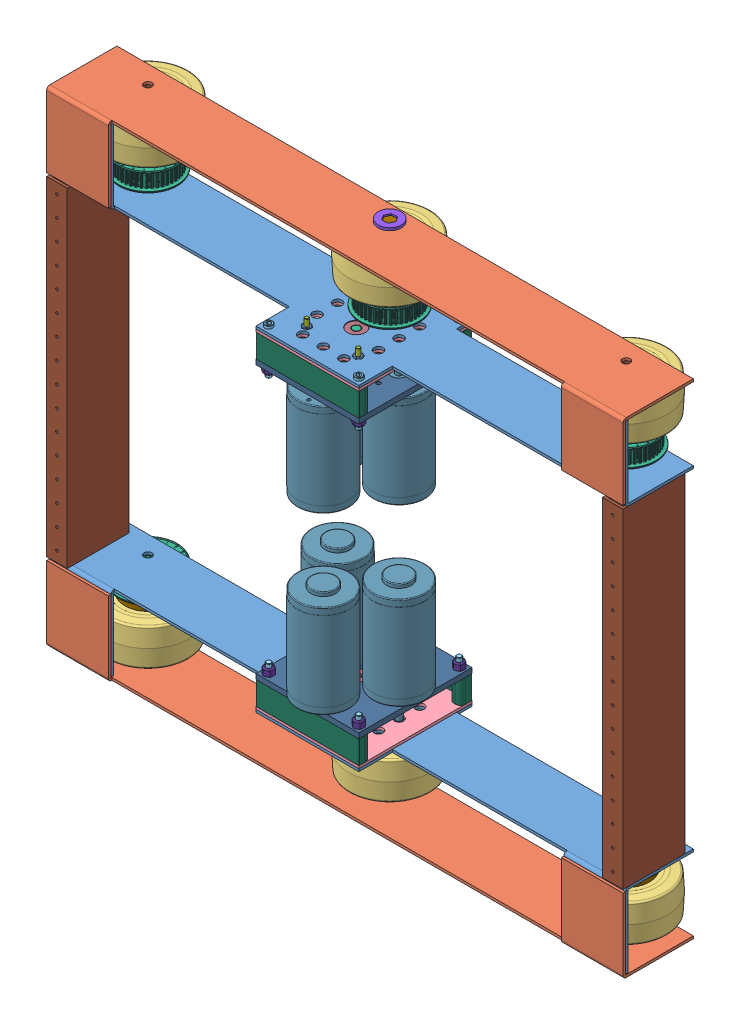
SolidWorks assembly DRIVE TRAIN, configuration Default. Lengths in mm.
Overall size (733.26 604.72 237.72).
116 component instances, 29 part files, 8 mates.
Components (placement in the parent):
- wheel well assembly-1: wheel well assembly [Default] at (270.1383 302.7916 604.4293) size (722.23 256.81 237.72)
  - interior wheel well-1: interior wheel well [Default] at (64.0134 461.709 590.6846) size (711.2 92.08 139.7)
  - exterior wheel well-1: exterior wheel well [Default] at (562.6642 549.3506 593.8596) x (-1 0 0) z (0 0 1) size (711.2 92.07 86.72)
  - wheel live axis-1: wheel live axis [Default] at (260.8798 526.3795 516.7847) x (0 -1 0) z (0.083749 0 0.996487) size (93.59 101.6 101.6)
    - colson wheel-1: colson wheel [Default] at (7.8533 43.785 105.4789) size (47.77 101.6 101.6)
    - hub live axis-1: hub live axis [Default] at (-17.6186 43.785 105.4789) x (0 -0.5 -0.866025) z (1 0 0) size (34.92 34.92 48.22)
    - versahub .5 in hex-2: versahub .5 in hex [Default] at (44.4376 43.785 105.4789) x (-1 0 0) z (0 0 -1) size (12.7 55.88 55.88)
    - pulley-1: pulley [Default] at (42.8501 43.785 105.4789) x (0 0.128986 0.991646) z (-1 0 0) size (73 73 23.01)
    - versahub 1.125 in bearing pilot-1: versahub 1.125 in bearing pilot [Default] at (38.0876 43.785 105.4789) x (0 -0.011158 0.999938) z (0 0.999938 0.011158) size (55.88 12.7 55.88)
    - hex bearing for live axis-1: hex bearing for live axis [Default] at (-30.3186 43.785 105.4789) x (0 -0.5 0.866025) z (0 0.866025 0.5) size (31.12 7.94 31.12)
  - wheel dead axis-1: wheel dead axis [Default] at (704.3486 556.3797 624.3714) x (0 -1 0) z (-0.767501 0 -0.641048) size (87.16 101.6 101.6)
    - colson wheel-1: colson wheel [Default] at (34.5983 59.2472 75.5116) size (47.77 101.6 101.6)
    - hub dead axis-1: hub dead axis [Default] at (61.6576 59.2472 75.5116) x (0 0.55376 0.832676) z (-1 0 0) size (57.15 57.15 47.62)
    - bearing-1: bearing [Default] at (57.6889 59.2472 75.5116) size (7.14 22.23 22.23)
    - bearing-2: bearing [Default] at (17.2074 59.2472 75.5116) size (7.14 22.23 22.23)
    - versahub 1.125 in bearing pilot-1: versahub 1.125 in bearing pilot [Default] at (68.0076 59.2472 75.5116) x (0 1 0) z (0 0 1) size (55.88 12.7 55.88)
    - pulley-1: pulley [Default] at (90.5951 59.2472 75.5116) x (0 0 -1) z (1 0 0) size (73 73 23.01)
    - spacer for dead axis-2: spacer for dead axis [Default] at (6.0316 59.2472 75.5116) x (0 0.370269 -0.928924) z (1 0 0) size (30.04 30.04 11.18)
  - wheel dead axis-2: wheel dead axis [Default] at (-40.9827 556.3797 545.9255) x (0 -1 0) z (0 0 1) size (87.16 101.6 101.6)
    - colson wheel-1: colson wheel [Default] at (34.5983 59.2472 75.5116) size (47.77 101.6 101.6)
    - hub dead axis-1: hub dead axis [Default] at (61.6576 59.2472 75.5116) x (0 0.55376 0.832676) z (-1 0 0) size (57.15 57.15 47.62)
    - bearing-1: bearing [Default] at (57.6889 59.2472 75.5116) size (7.14 22.23 22.23)
    - bearing-2: bearing [Default] at (17.2074 59.2472 75.5116) size (7.14 22.23 22.23)
    - versahub 1.125 in bearing pilot-1: versahub 1.125 in bearing pilot [Default] at (68.0076 59.2472 75.5116) x (0 1 0) z (0 0 1) size (55.88 12.7 55.88)
    - pulley-1: pulley [Default] at (90.5951 59.2472 75.5116) x (0 0 -1) z (1 0 0) size (73 73 23.01)
    - spacer for dead axis-2: spacer for dead axis [Default] at (6.0316 59.2472 75.5116) x (0 0.370269 -0.928924) z (1 0 0) size (30.04 30.04 11.18)
  - 3CIM Gearbox with plate - AM14U-1: 3CIM Gearbox with plate - AM14U [Default] at (236.214 396.9903 599.8023) x (0.425715 0 -0.904857) z (0 -1 0) size (180.67 174.39 255.11)
    - 500 E-klip-1: 500 E-klip [Default] at (16.1298 77.6456 -43.9601) x (-0.987566 -0.157207 0) z (0 0 1) size (19.07 20.96 1.27)
    - FR6ZZ Bearing-1: FR6ZZ Bearing [Default] at (-13.0875 102.2889 -55.8473) x (0.991783 0.127931 0) z (0 0 -1) size (24.69 24.69 7.16)
    - CIM Motor SW-1: CIM Motor SW [Default] at (-100.8929 87.6226 -3.2185) x (0 1 0) z (0 0 -1) size (64.01 64.01 154.94)
    - ex-2508 Spacer-1: ex-2508 Spacer [Default] at (-92.2921 67.2369 -57.3713) x (0.425715 0.904857 0) z (0 0 1) size (127 14.35 28.75)
    - CIM Motor SW-2: CIM Motor SW [Default] at (-101.4872 6.1263 -3.2185) x (-0.762709 0.646742 0) z (0 0 -1) size (64.01 64.01 154.94)
    - Toughbox 14T Small Cluster-1: Toughbox 14T Small Cluster [Default] at (-21.1033 95.1629 -40.7851) x (-0.837052 0.547123 0) z (0 0 -1) size (20.03 20.32 15.25)
    - 14-20 Nylock Nut_97135A210-1: 14-20 Nylock Nut_97135A210 [Default] at (19.7748 14.5119 -22.2685) x (1 0 0) z (0 -1 0) size (11.11 8.13 12.83)
    - Toughbox 50T Large Cluster-1: Toughbox 50T Large Cluster [Default] at (-21.1033 95.1629 -40.7851) x (-0.055297 -0.99847 0) z (0 0 1) size (65.97 66.04 10.34)
    - 10-32 Nylock Jam Nut_90633A411-1: 10-32 Nylock Jam Nut_90633A411 [Default] at (-34.2188 136.4219 -60.5463) x (0.976554 -0.215274 0) z (0.215274 0.976554 0) size (9.53 4.55 11)
    - 14-20 Nylock Nut_97135A210-2: 14-20 Nylock Nut_97135A210 [Default] at (67.0932 115.0872 -22.2685) x (1 0 0) z (0 -1 0) size (11.11 8.13 12.83)
    - 14-20 Nylock Nut_97135A210-3: 14-20 Nylock Nut_97135A210 [Default] at (-92.2921 67.2369 -22.2685) x (1 0 0) z (0 -1 0) size (11.11 8.13 12.83)
    - ex-2508 Spacer-2: ex-2508 Spacer [Default] at (67.0932 115.0872 -57.3713) x (-0.425715 -0.904857 0) z (0 0 1) size (127 14.35 28.75)
    - Toughbox 50T Output-1: Toughbox 50T Output [Default] at (16.1298 77.6456 -45.1793) x (1 0 0) z (0 0 -1) size (65.97 66.04 10.62)
    - FR6ZZ Bearing-2: FR6ZZ Bearing [Default] at (-30.482 100.3659 -30.1425) x (-0.995778 -0.091798 0) z (0 0 1) size (24.69 24.69 7.16)
    - FR8ZZ Hex Bearing-1: FR8ZZ Hex Bearing [Default] at (16.1298 77.6456 -63.2666) size (31.12 31.12 7.93)
    - FR6ZZ Bearing-3: FR6ZZ Bearing [Default] at (7.2113 83.6032 -29.1773) x (-0.999955 -0.009486 0) z (0 0 1) size (24.69 24.69 7.16)
    - 3CIM TB Special Shaft Plate-1: 3CIM TB Special Shaft Plate [Default] at (16.1298 77.6456 -57.3713) x (0.425715 0.904857 0) z (0 0 1) size (127 139.7 3.17)
    - 10-32 Nylock Jam Nut_90633A411-2: 10-32 Nylock Jam Nut_90633A411 [Default] at (-61.2517 78.9634 -60.5463) x (0.733502 -0.679687 0) z (0.679687 0.733502 0) size (9.53 4.55 11)
    - SHCS 14-20 x 2-1: SHCS 14-20 x 2 [Default] at (-44.9737 167.8122 -67.0995) x (0.867127 -0.498087 0) z (0.498087 0.867127 0) size (9.53 57.35 9.53)
    - CIM Motor SW-3: CIM Motor SW [Default] at (-138.5887 47.3684 -3.2185) x (0.249226 0.968445 0) z (0 0 -1) size (64.01 64.01 154.94)
    - SHCS 14-20 x 2-2: SHCS 14-20 x 2 [Default] at (67.0932 115.0872 -67.0995) x (1 0 0) z (0 1 0) size (9.53 57.35 9.53)
    - TB Hex Shaft-1: TB Hex Shaft [Default] at (-63.6271 92.3312 -31.1331) x (-0.892349 -0.451347 0) z (-0.451347 0.892349 0) size (11 38.23 9.52)
    - 10-32x0625_shcs_HX-SHCS 0.19-32x1.375x1-C-1: 10-32x0625_shcs_HX-SHCS 0.19-32x1.375x1-C [Default] at (-34.2188 136.4219 -52.5453) x (0 0 -1) z (0.658531 0.752554 0) size (20.7 7.94 7.94)
    - Toughbox d29a-1: Toughbox d29a [Default] at (16.1298 77.6456 -22.2685) x (-0.904857 0.425715 0) z (0.425715 0.904857 0) size (19.05 6.1 50.8)
    - SHCS 14-20 x 2-3: SHCS 14-20 x 2 [Default] at (19.7748 14.5119 -67.0995) x (1 0 0) z (0 1 0) size (9.53 57.35 9.53)
    - 14-20 Nylock Nut_97135A210-4: 14-20 Nylock Nut_97135A210 [Default] at (-44.9737 167.8122 -22.2685) x (1 0 0) z (0 -1 0) size (11.11 8.13 12.83)
    - TB Output Shaft Hex L-Base 2-1: TB Output Shaft Hex L-Base 2 [Default] at (20.8476 119.155 -54.5773) x (0.5 0.866025 0) z (-0.866025 0.5 0) size (14.66 148.64 12.7)
    - 3CIM TB Special Motor Plate-1: 3CIM TB Special Motor Plate [Default] at (16.1298 77.6456 -57.1935) x (0.425715 0.904857 0) z (0 0 1) size (127 139.7 6.35)
    - 10-32x0625_shcs_HX-SHCS 0.19-32x1.375x1-C-2: 10-32x0625_shcs_HX-SHCS 0.19-32x1.375x1-C [Default] at (-61.2517 78.9634 -52.5453) x (0 0 -1) z (1 0 0) size (20.7 7.94 7.94)
    - SHCS 14-20 x 2-4: SHCS 14-20 x 2 [Default] at (-92.2921 67.2369 -67.0995) x (1 0 0) z (0 1 0) size (9.53 57.35 9.53)
- wheel well assembly-2: wheel well assembly [Default] at (896.816 811.4646 604.4293) x (-1 0 0) z (0 0 1) size (722.23 256.81 237.72)
  - interior wheel well-1: interior wheel well [Default] at (64.0134 461.709 590.6846) size (711.2 92.08 139.7)
  - exterior wheel well-1: exterior wheel well [Default] at (562.6642 549.3506 593.8596) x (-1 0 0) z (0 0 1) size (711.2 92.07 86.72)
  - wheel live axis-1: wheel live axis [Default] at (260.8798 526.3795 516.7847) x (0 -1 0) z (0.083749 0 0.996487) size (93.59 101.6 101.6)
    - colson wheel-1: colson wheel [Default] at (7.8533 43.785 105.4789) size (47.77 101.6 101.6)
    - hub live axis-1: hub live axis [Default] at (-17.6186 43.785 105.4789) x (0 -0.5 -0.866025) z (1 0 0) size (34.92 34.92 48.22)
    - versahub .5 in hex-2: versahub .5 in hex [Default] at (44.4376 43.785 105.4789) x (-1 0 0) z (0 0 -1) size (12.7 55.88 55.88)
    - pulley-1: pulley [Default] at (42.8501 43.785 105.4789) x (0 0.128986 0.991646) z (-1 0 0) size (73 73 23.01)
    - versahub 1.125 in bearing pilot-1: versahub 1.125 in bearing pilot [Default] at (38.0876 43.785 105.4789) x (0 -0.011158 0.999938) z (0 0.999938 0.011158) size (55.88 12.7 55.88)
    - hex bearing for live axis-1: hex bearing for live axis [Default] at (-30.3186 43.785 105.4789) x (0 -0.5 0.866025) z (0 0.866025 0.5) size (31.12 7.94 31.12)
  - wheel dead axis-1: wheel dead axis [Default] at (704.3486 556.3797 624.3714) x (0 -1 0) z (-0.767501 0 -0.641048) size (87.16 101.6 101.6)
    - colson wheel-1: colson wheel [Default] at (34.5983 59.2472 75.5116) size (47.77 101.6 101.6)
    - hub dead axis-1: hub dead axis [Default] at (61.6576 59.2472 75.5116) x (0 0.55376 0.832676) z (-1 0 0) size (57.15 57.15 47.62)
    - bearing-1: bearing [Default] at (57.6889 59.2472 75.5116) size (7.14 22.23 22.23)
    - bearing-2: bearing [Default] at (17.2074 59.2472 75.5116) size (7.14 22.23 22.23)
    - versahub 1.125 in bearing pilot-1: versahub 1.125 in bearing pilot [Default] at (68.0076 59.2472 75.5116) x (0 1 0) z (0 0 1) size (55.88 12.7 55.88)
    - pulley-1: pulley [Default] at (90.5951 59.2472 75.5116) x (0 0 -1) z (1 0 0) size (73 73 23.01)
    - spacer for dead axis-2: spacer for dead axis [Default] at (6.0316 59.2472 75.5116) x (0 0.370269 -0.928924) z (1 0 0) size (30.04 30.04 11.18)
  - wheel dead axis-2: wheel dead axis [Default] at (-40.9827 556.3797 545.9255) x (0 -1 0) z (0 0 1) size (87.16 101.6 101.6)
    - colson wheel-1: colson wheel [Default] at (34.5983 59.2472 75.5116) size (47.77 101.6 101.6)
    - hub dead axis-1: hub dead axis [Default] at (61.6576 59.2472 75.5116) x (0 0.55376 0.832676) z (-1 0 0) size (57.15 57.15 47.62)
    - bearing-1: bearing [Default] at (57.6889 59.2472 75.5116) size (7.14 22.23 22.23)
    - bearing-2: bearing [Default] at (17.2074 59.2472 75.5116) size (7.14 22.23 22.23)
    - versahub 1.125 in bearing pilot-1: versahub 1.125 in bearing pilot [Default] at (68.0076 59.2472 75.5116) x (0 1 0) z (0 0 1) size (55.88 12.7 55.88)
    - pulley-1: pulley [Default] at (90.5951 59.2472 75.5116) x (0 0 -1) z (1 0 0) size (73 73 23.01)
    - spacer for dead axis-2: spacer for dead axis [Default] at (6.0316 59.2472 75.5116) x (0 0.370269 -0.928924) z (1 0 0) size (30.04 30.04 11.18)
  - 3CIM Gearbox with plate - AM14U-1: 3CIM Gearbox with plate - AM14U [Default] at (236.214 396.9903 599.8023) x (0.425715 0 -0.904857) z (0 -1 0) size (180.67 174.39 255.11)
    - 500 E-klip-1: 500 E-klip [Default] at (16.1298 77.6456 -43.9601) x (-0.987566 -0.157207 0) z (0 0 1) size (19.07 20.96 1.27)
    - FR6ZZ Bearing-1: FR6ZZ Bearing [Default] at (-13.0875 102.2889 -55.8473) x (0.991783 0.127931 0) z (0 0 -1) size (24.69 24.69 7.16)
    - CIM Motor SW-1: CIM Motor SW [Default] at (-100.8929 87.6226 -3.2185) x (0 1 0) z (0 0 -1) size (64.01 64.01 154.94)
    - ex-2508 Spacer-1: ex-2508 Spacer [Default] at (-92.2921 67.2369 -57.3713) x (0.425715 0.904857 0) z (0 0 1) size (127 14.35 28.75)
    - CIM Motor SW-2: CIM Motor SW [Default] at (-101.4872 6.1263 -3.2185) x (-0.762709 0.646742 0) z (0 0 -1) size (64.01 64.01 154.94)
    - Toughbox 14T Small Cluster-1: Toughbox 14T Small Cluster [Default] at (-21.1033 95.1629 -40.7851) x (-0.837052 0.547123 0) z (0 0 -1) size (20.03 20.32 15.25)
    - 14-20 Nylock Nut_97135A210-1: 14-20 Nylock Nut_97135A210 [Default] at (19.7748 14.5119 -22.2685) x (1 0 0) z (0 -1 0) size (11.11 8.13 12.83)
    - Toughbox 50T Large Cluster-1: Toughbox 50T Large Cluster [Default] at (-21.1033 95.1629 -40.7851) x (-0.055297 -0.99847 0) z (0 0 1) size (65.97 66.04 10.34)
    - 10-32 Nylock Jam Nut_90633A411-1: 10-32 Nylock Jam Nut_90633A411 [Default] at (-34.2188 136.4219 -60.5463) x (0.976554 -0.215274 0) z (0.215274 0.976554 0) size (9.53 4.55 11)
    - 14-20 Nylock Nut_97135A210-2: 14-20 Nylock Nut_97135A210 [Default] at (67.0932 115.0872 -22.2685) x (1 0 0) z (0 -1 0) size (11.11 8.13 12.83)
    - 14-20 Nylock Nut_97135A210-3: 14-20 Nylock Nut_97135A210 [Default] at (-92.2921 67.2369 -22.2685) x (1 0 0) z (0 -1 0) size (11.11 8.13 12.83)
    - ex-2508 Spacer-2: ex-2508 Spacer [Default] at (67.0932 115.0872 -57.3713) x (-0.425715 -0.904857 0) z (0 0 1) size (127 14.35 28.75)
    - Toughbox 50T Output-1: Toughbox 50T Output [Default] at (16.1298 77.6456 -45.1793) x (1 0 0) z (0 0 -1) size (65.97 66.04 10.62)
    - FR6ZZ Bearing-2: FR6ZZ Bearing [Default] at (-30.482 100.3659 -30.1425) x (-0.995778 -0.091798 0) z (0 0 1) size (24.69 24.69 7.16)
    - FR8ZZ Hex Bearing-1: FR8ZZ Hex Bearing [Default] at (16.1298 77.6456 -63.2666) size (31.12 31.12 7.93)
    - FR6ZZ Bearing-3: FR6ZZ Bearing [Default] at (7.2113 83.6032 -29.1773) x (-0.999955 -0.009486 0) z (0 0 1) size (24.69 24.69 7.16)
    - 3CIM TB Special Shaft Plate-1: 3CIM TB Special Shaft Plate [Default] at (16.1298 77.6456 -57.3713) x (0.425715 0.904857 0) z (0 0 1) size (127 139.7 3.17)
    - 10-32 Nylock Jam Nut_90633A411-2: 10-32 Nylock Jam Nut_90633A411 [Default] at (-61.2517 78.9634 -60.5463) x (0.733502 -0.679687 0) z (0.679687 0.733502 0) size (9.53 4.55 11)
    - SHCS 14-20 x 2-1: SHCS 14-20 x 2 [Default] at (-44.9737 167.8122 -67.0995) x (0.867127 -0.498087 0) z (0.498087 0.867127 0) size (9.53 57.35 9.53)
    - CIM Motor SW-3: CIM Motor SW [Default] at (-138.5887 47.3684 -3.2185) x (0.249226 0.968445 0) z (0 0 -1) size (64.01 64.01 154.94)
    - SHCS 14-20 x 2-2: SHCS 14-20 x 2 [Default] at (67.0932 115.0872 -67.0995) x (1 0 0) z (0 1 0) size (9.53 57.35 9.53)
    - TB Hex Shaft-1: TB Hex Shaft [Default] at (-63.6271 92.3312 -31.1331) x (-0.892349 -0.451347 0) z (-0.451347 0.892349 0) size (11 38.23 9.52)
    - 10-32x0625_shcs_HX-SHCS 0.19-32x1.375x1-C-1: 10-32x0625_shcs_HX-SHCS 0.19-32x1.375x1-C [Default] at (-34.2188 136.4219 -52.5453) x (0 0 -1) z (0.658531 0.752554 0) size (20.7 7.94 7.94)
    - Toughbox d29a-1: Toughbox d29a [Default] at (16.1298 77.6456 -22.2685) x (-0.904857 0.425715 0) z (0.425715 0.904857 0) size (19.05 6.1 50.8)
    - SHCS 14-20 x 2-3: SHCS 14-20 x 2 [Default] at (19.7748 14.5119 -67.0995) x (1 0 0) z (0 1 0) size (9.53 57.35 9.53)
    - 14-20 Nylock Nut_97135A210-4: 14-20 Nylock Nut_97135A210 [Default] at (-44.9737 167.8122 -22.2685) x (1 0 0) z (0 -1 0) size (11.11 8.13 12.83)
    - TB Output Shaft Hex L-Base 2-1: TB Output Shaft Hex L-Base 2 [Default] at (20.8476 119.155 -54.5773) x (0.5 0.866025 0) z (-0.866025 0.5 0) size (14.66 148.64 12.7)
    - 3CIM TB Special Motor Plate-1: 3CIM TB Special Motor Plate [Default] at (16.1298 77.6456 -57.1935) x (0.425715 0.904857 0) z (0 0 1) size (127 139.7 6.35)
    - 10-32x0625_shcs_HX-SHCS 0.19-32x1.375x1-C-2: 10-32x0625_shcs_HX-SHCS 0.19-32x1.375x1-C [Default] at (-61.2517 78.9634 -52.5453) x (0 0 -1) z (1 0 0) size (20.7 7.94 7.94)
    - SHCS 14-20 x 2-4: SHCS 14-20 x 2 [Default] at (-92.2921 67.2369 -67.0995) x (1 0 0) z (0 1 0) size (9.53 57.35 9.53)
- tuuuube-1: tuuuube [Default] at (240.5772 353.9281 1252.2638) x (-1 0 0) z (0 1 0) size (25.4 76.2 406.4)
- tuuuube-3: tuuuube [Default] at (926.3772 353.9281 1252.2638) x (-1 0 0) z (0 1 0) size (25.4 76.2 406.4)
Mates (geometry in assembly coordinates):
- Coincident4: coincident anti-aligned: plane of wheel well assembly-2/interior wheel well-1 through (939.0772 353.9281 1203.6413) normal (0 1 0); plane of tuuuube-1 through (240.5772 353.9281 1252.2638) normal (0 -1 0)
- Coincident6: coincident aligned: line of wheel well assembly-2/interior wheel well-1 through (227.8772 353.9281 1203.6413) axis (0 0 1); line of tuuuube-1 through (227.8772 353.9281 1214.1638) axis (0 0 1)
- Coincident9: coincident aligned: plane of wheel well assembly-2/exterior wheel well-1 through (227.8772 175.3915 1290.3638) normal (0 0 1); plane of tuuuube-1 through (253.2772 760.3281 1290.3638) normal (0 0 1)
- Coincident13: coincident aligned: line of wheel well assembly-1/interior wheel well-1 through (227.8772 760.3281 1203.6413) axis (0 0 1); line of tuuuube-1 through (227.8772 760.3281 1214.1638) axis (0 0 1)
- Coincident14: coincident aligned: plane of wheel well assembly-1/exterior wheel well-1 through (939.0772 938.8647 1290.3638) normal (0 0 1); plane of tuuuube-1 through (253.2772 760.3281 1290.3638) normal (0 0 1)
- Coincident15: coincident aligned: plane of wheel well assembly-2/exterior wheel well-1 through (227.8772 175.3915 1290.3638) normal (0 0 1); plane of tuuuube-3 through (939.0772 760.3281 1290.3638) normal (0 0 1)
- Coincident16: coincident anti-aligned: line of wheel well assembly-1/interior wheel well-1 through (939.0772 760.3281 1203.6413) axis (0 0 1); line of tuuuube-3 through (939.0772 760.3281 1290.3638) axis (0 0 -1)
- Coincident17: coincident anti-aligned: line of wheel well assembly-2/interior wheel well-1 through (939.0772 353.9281 1203.6413) axis (0 0 1); line of tuuuube-3 through (939.0772 353.9281 1290.3638) axis (0 0 -1)
